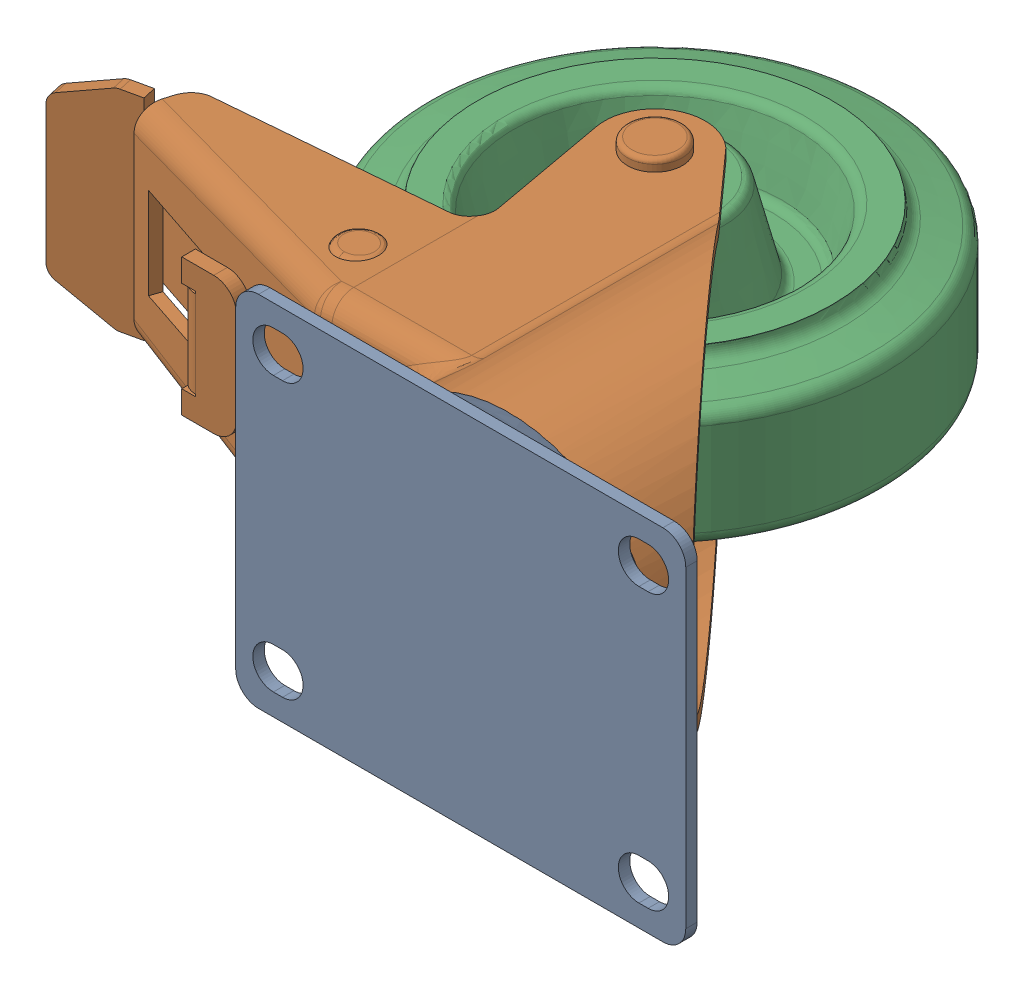
SolidWorks assembly 99999-004-07-00, configuration Default. Lengths in mm.
Overall size (177.73 78.5 132.5).
3 component instances, 3 part files, 0 mates.
Components (placement in the parent):
- 99999-004-07-01-1: 99999-004-07-01 [Default] at origin size (98.5 78.5 10.5)
- 99999-004-07-02-1: 99999-004-07-02 [Default] x (1 0 0) z (0 0 -1) size (162.23 67.5 91)
- 99999-004-07-03-1: 99999-004-07-03 [Default] at (-40 0 -80) x (0 -1 0) z (0 0 1) size (45 100 100)
